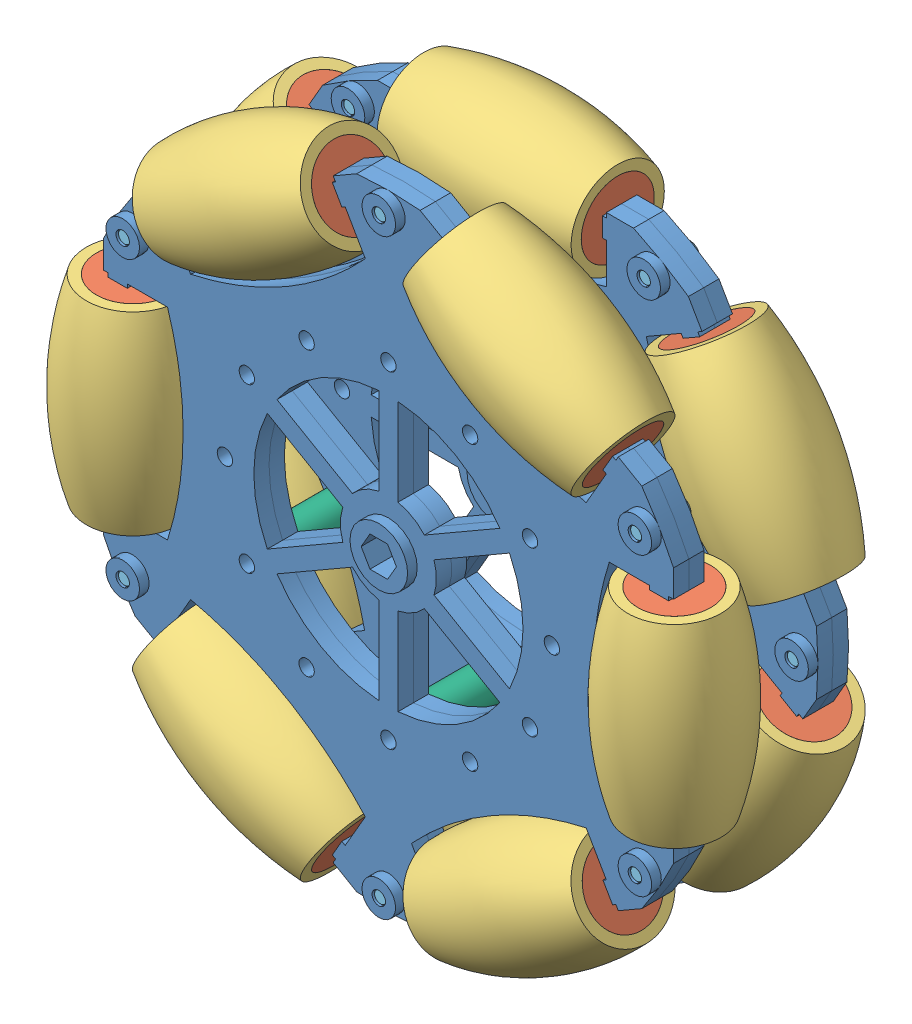
SolidWorks assembly Omni-wheel, configuration Default. Lengths in mm.
Overall size (184.29 186.74 49.75).
25 component instances, 6 part files, 6 mates.
Components (placement in the parent):
- Omni-wheel half-1: Omni-wheel half [Default] at (0 0 -12.175) x (1 0 0) z (0 0 -1) size (134.46 138 25.4)
  - Disc-1: Disc [Default] at (0 0 -1.5875) x (-1 0 0) z (0 0 -1) size (130 118.6 5.17)
  - RollerCore-1: RollerCore [Default] at origin size (130.84 134 21.4)
  - RollerSkin-1: RollerSkin [Default] at origin size (134.46 138 25.4)
  - RollerAxle-1: RollerAxle [Default] at origin size (123.25 114.4 1.8)
  - Disc-2: Disc [Default no hub] at (0 0 1.5875) x (-1 0 0) z (0 0 -1) size (130 118.6 3.17)
  - Metric button hex socket screw-2: Metric button hex socket screw [ISO 7380 - M3 x 8 --- 8C] at (30.75 -53.2606 4.825) x (0 0 -1) z (1 0 0) size (9.65 5.7 5.7)
  - Metric button hex socket screw-3: Metric button hex socket screw [ISO 7380 - M3 x 8 --- 8C] at (61.5 0 4.825) x (0 0 -1) z (1 0 0) size (9.65 5.7 5.7)
  - Metric button hex socket screw-4: Metric button hex socket screw [ISO 7380 - M3 x 8 --- 8C] at (30.75 53.2606 4.825) x (0 0 -1) z (1 0 0) size (9.65 5.7 5.7)
  - Metric button hex socket screw-5: Metric button hex socket screw [ISO 7380 - M3 x 8 --- 8C] at (-30.75 53.2606 4.825) x (0 0 -1) z (1 0 0) size (9.65 5.7 5.7)
  - Metric button hex socket screw-7: Metric button hex socket screw [ISO 7380 - M3 x 8 --- 8C] at (-61.5 0 4.825) x (0 0 -1) z (-1 0 0) size (9.65 5.7 5.7)
  - Metric button hex socket screw-8: Metric button hex socket screw [ISO 7380 - M3 x 8 --- 8C] at (-30.75 -53.2606 4.825) x (0 0 -1) z (-1 0 0) size (9.65 5.7 5.7)
- Omni-wheel half-2: Omni-wheel half [Mating Hex Axle] at (0 0 12.175) x (-0.866025 0.5 0) z (0 0 -1) size (134.46 138 25.4)
  - Disc-1: Disc [Mating Hex Axle] at (0 0 -1.5875) x (-1 0 0) z (0 0 -1) size (130 118.6 5.17)
  - RollerCore-1: RollerCore [Default] at origin size (130.84 134 21.4)
  - RollerSkin-1: RollerSkin [Default] at origin size (134.46 138 25.4)
  - RollerAxle-1: RollerAxle [Default] at origin size (123.25 114.4 1.8)
  - Disc-2: Disc [Mating Hex no hub] at (0 0 1.5875) x (-1 0 0) z (0 0 -1) size (130 118.6 3.17)
  - Metric button hex socket screw-2: Metric button hex socket screw [ISO 7380 - M3 x 8 --- 8C] at (30.75 -53.2606 4.825) x (0 0 -1) z (1 0 0) size (9.65 5.7 5.7)
  - Metric button hex socket screw-3: Metric button hex socket screw [ISO 7380 - M3 x 8 --- 8C] at (61.5 0 4.825) x (0 0 -1) z (1 0 0) size (9.65 5.7 5.7)
  - Metric button hex socket screw-4: Metric button hex socket screw [ISO 7380 - M3 x 8 --- 8C] at (30.75 53.2606 4.825) x (0 0 -1) z (1 0 0) size (9.65 5.7 5.7)
  - Metric button hex socket screw-5: Metric button hex socket screw [ISO 7380 - M3 x 8 --- 8C] at (-30.75 53.2606 4.825) x (0 0 -1) z (1 0 0) size (9.65 5.7 5.7)
  - Metric button hex socket screw-7: Metric button hex socket screw [ISO 7380 - M3 x 8 --- 8C] at (-61.5 0 4.825) x (0 0 -1) z (-1 0 0) size (9.65 5.7 5.7)
  - Metric button hex socket screw-8: Metric button hex socket screw [ISO 7380 - M3 x 8 --- 8C] at (-30.75 -53.2606 4.825) x (0 0 -1) z (-1 0 0) size (9.65 5.7 5.7)
- Wheel Standoffs-1: Wheel Standoffs [Default] at origin size (66.49 75.6 18)
Mates (geometry in assembly coordinates):
- Concentric10: concentric aligned: circle of Omni-wheel-half-1/Disc-1; circle of Omni-wheel-half-2/Disc-1
- Coincident2: coincident anti-aligned: plane of Omni-wheel half-1/Disc-1 through (0 0 -9) normal (0 0 1); plane of Wheel Standoffs-1 through (0 34 -9) normal (0 0 -1)
- Coincident4: coincident anti-aligned: plane of Omni-wheel half-1 through (0 0 -12.175) normal (0 -1 0)
- Coincident5: coincident aligned: plane of Omni-wheel half-1 through (0 0 -12.175) normal (1 0 0)
- Coincident8: coordinate: point of Wheel Standoffs-1
- Coincident9: coincident anti-aligned: plane of Omni-wheel half-2/Disc-2 through (0 0 9) normal (0 0 -1); plane of Wheel Standoffs-1 through (-29.4449 -17 9) normal (0 0 1)
